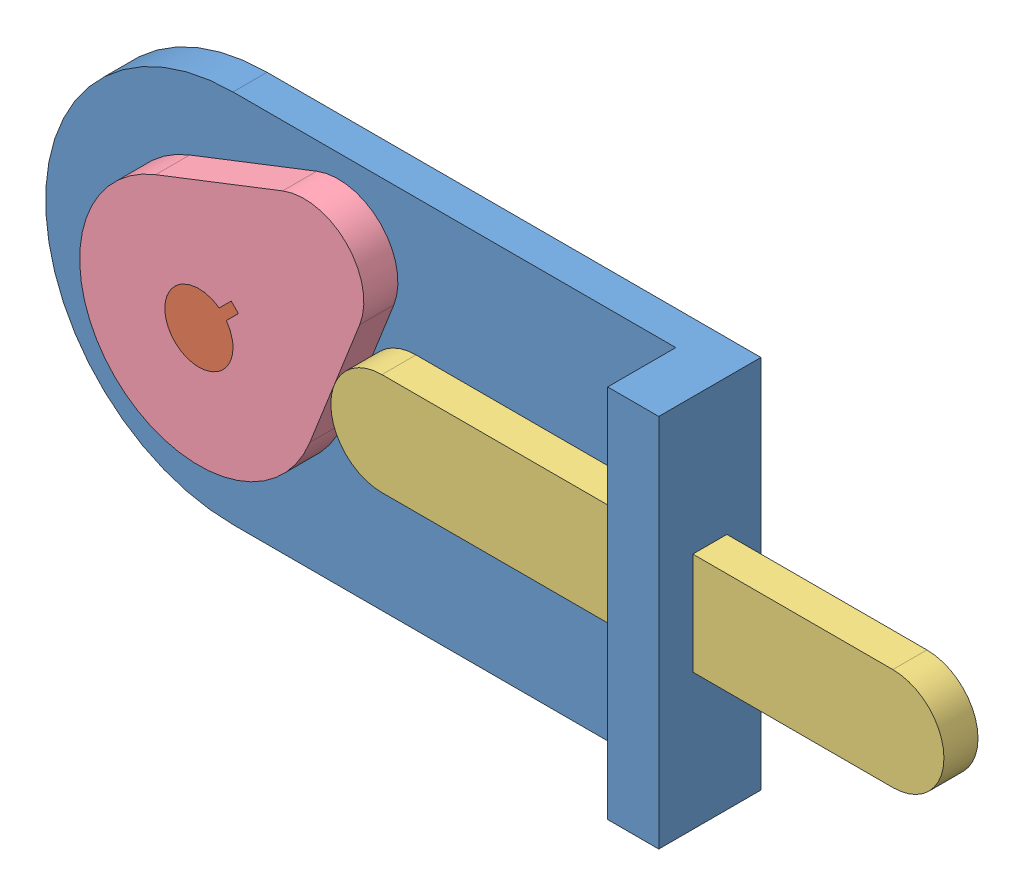
SolidWorks assembly HW8_WONG_P2, configuration Default. Lengths in mm.
Overall size (273.73 122.97 30).
4 component instances, 4 part files, 8 mates.
Components (placement in the parent):
- cam_base-1: cam_base [Default] at origin size (200 110 30)
- cam_pin-1: cam_pin [Default] at (-25.5435 31.3556 0) x (0.70823 0.705982 0) z (0.705982 -0.70823 0) size (24.88 20 19.99)
- can_bar-1: can_bar [Default] at (-6.0933 -27.8226 0) size (180 30 10)
- cam-2: cam [Default] at (-59.8185 -27.8226 0) x (0.70823 0.705982 0) z (0.705982 -0.70823 0) size (96.16 10 70)
Mates (geometry in assembly coordinates):
- Concentric1: concentric aligned: cylinder of cam_base-1 through (-59.8185 -27.8226 -10) axis (0 0 1) radius 5; cylinder of cam_pin-1 through (-59.8185 -27.8226 -10) axis (0 0 1) radius 5
- Coincident2: coincident anti-aligned: plane of cam_base-1 through (0 0 0) normal (0 0 1); plane of cam_pin-1 through (-25.5435 31.3556 0) normal (0 0 -1)
- Concentric2: concentric aligned: cylinder of cam_pin-1 through (-59.8185 -27.8226 10) axis (0 0 -1) radius 9.9965; cylinder of cam-2 through (-59.8185 -27.8226 10) axis (0 0 -1) radius 10
- Parallel1: parallel anti-aligned: plane of cam_pin-1 through (-61.7836 -4.7695 10) normal (0.70823 0.705982 0); plane of cam-2 through (-49.2751 -17.3128 10) normal (-0.70823 -0.705982 0)
- Coincident4: coincident aligned: plane of cam_pin-1 through (-25.5435 31.3556 10) normal (0 0 1); plane of cam-2 through (-59.8185 -27.8226 10) normal (0 0 1)
- Coincident5: coincident anti-aligned: plane of cam_base-1 through (65.1815 -42.8226 10) normal (0 1 0); plane of can_bar-1 through (143.9067 -42.8226 10) normal (0 -1 0)
- Coincident6: coincident anti-aligned: plane of cam_base-1 through (65.1815 -12.8226 10) normal (0 0 -1); plane of can_bar-1 through (-6.0933 -27.8226 10) normal (0 0 1)
- CamMateTangent1: cam tangent anti-aligned: plane of cam-2 through (-27.2453 -40.6284 10) normal (0.930662 -0.365879 0); cylinder of can_bar-1 through (-6.0933 -27.8226 10) axis (0 0 -1) radius 15
